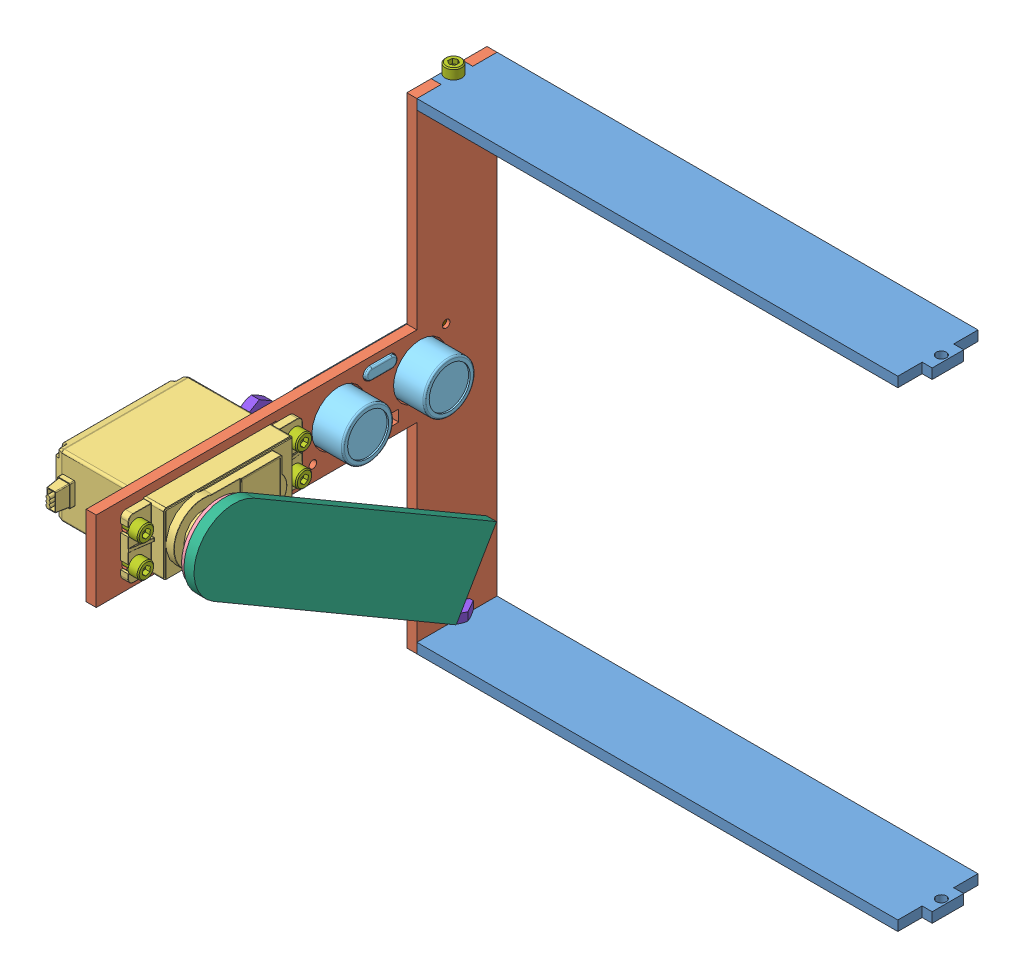
SolidWorks assembly midterm, configuration Default. Lengths in mm.
Overall size (184.49 158.75 127).
20 component instances, 9 part files, 38 mates.
Components (placement in the parent):
- midterm backwall-1: midterm backwall [Default] at (21.857 79.3906 28.0578) size (158.76 3.18 25.4)
- midterm backwall-2: midterm backwall [Default] at (21.857 -69.8294 28.0578) size (158.76 3.18 25.4)
- midtermfrontwall2-1: midtermfrontwall2 [Default] at (-54.343 6.3706 28.0578) x (0 0 -1) z (0 1 0) size (127 3.18 152.4)
- Standard Servo FS5106B-1: Standard Servo FS5106B [Default] at (-56.248 6.5281 107.0078) x (0 0 -1) z (1 0 0) size (55.2 19.69 44.46)
- Micro Servo Horn Round-1: Micro Servo Horn Round [Default] at (-40.2989 6.5281 117.5153) x (0 0.094238 0.99555) z (0 0.99555 -0.094238) size (23.65 4.35 23.65)
- HC-SR04 WITH CONFIGURATIONS-1: HC-SR04 WITH CONFIGURATIONS [With Oscillator] at (-59.223 7.3667 52.5952) x (0 0 -1) z (1 0 0) size (45.2 26.75 18.52)
- midterm arm-1: midterm arm [Default] at (-35.506 -15.8788 79.1261) x (0 0.863649 -0.504093) z (0 0.504093 0.863649) size (25.4 3.18 101.6)
- socket head cap screw_ai-1: socket head cap screw_ai [HX-SHCS 0.125-44x0.4375x0.4375-N] at (-55.433 -73.0044 28.0578) x (0 1 0) z (0 0 1) size (14.29 5.21 5.21)
- socket head cap screw_ai-2: socket head cap screw_ai [HX-SHCS 0.125-44x0.4375x0.4375-N] at (-55.433 85.7456 28.0578) x (0 -1 0) z (-0.546944 0 0.837169) size (14.29 5.21 5.21)
- socket head cap screw_ai-3: socket head cap screw_ai [HX-SHCS 0.125-44x0.4375x0.4375-N] at (-48.755 1.4481 81.9588) x (-1 0 0) z (0 0.924225 0.381849) size (14.29 5.21 5.21)
- socket head cap screw_ai-4: socket head cap screw_ai [HX-SHCS 0.125-44x0.4375x0.4375-N] at (-48.755 11.6081 81.9588) x (-1 0 0) z (0 -0.924225 -0.381849) size (14.29 5.21 5.21)
- socket head cap screw_ai-5: socket head cap screw_ai [HX-SHCS 0.125-44x0.4375x0.4375-N] at (-48.755 1.4481 132.0568) x (-1 0 0) z (0 0.924225 0.381849) size (14.29 5.21 5.21)
- socket head cap screw_ai-6: socket head cap screw_ai [HX-SHCS 0.125-44x0.4375x0.4375-N] at (-48.755 11.6081 132.0568) x (-1 0 0) z (0 -0.924225 -0.381849) size (14.29 5.21 5.21)
- machine screw nut hex_ai-1: machine screw nut hex_ai [MSHXNUT 0.125-44-S-N] at (-58.3201 1.4481 132.0568) x (0 0 -1) z (1 0 0) size (7.92 9.15 2.9)
- machine screw nut hex_ai-3: machine screw nut hex_ai [MSHXNUT 0.125-44-S-N] at (-57.024 11.6081 132.0568) x (0 0 -1) z (1 0 0) size (7.92 9.15 2.9)
- machine screw nut hex_ai-4: machine screw nut hex_ai [MSHXNUT 0.125-44-S-N] at (-58.084 1.4481 81.9588) x (0 0 -1) z (1 0 0) size (7.92 9.15 2.9)
- machine screw nut hex_ai-5: machine screw nut hex_ai [MSHXNUT 0.125-44-S-N] at (-65.9381 11.6081 81.9588) x (0 0 1) z (-1 0 0) size (7.92 9.15 2.9)
- machine screw nut hex_ai-8: machine screw nut hex_ai [MSHXNUT 0.125-44-S-N] at (-55.433 78.3479 28.0578) x (0.999955 0 -0.009478) z (0 1 0) size (7.92 9.15 2.9)
- machine screw nut hex_ai-9: machine screw nut hex_ai [MSHXNUT 0.125-44-S-N] at (-55.433 -65.7993 28.0578) x (-0.009669 0 0.999953) z (0 -1 0) size (7.92 9.15 2.9)
- socket button head cap screw_ai-7: socket button head cap screw_ai [SBHCSCREW 0.086-64x0.3125-HX-N] at (-64.2211 16.1167 31.4952) size (9.11 4.17 4.17)
Mates (geometry in assembly coordinates):
- Coincident19: coincident anti-aligned: plane of midterm backwall-2 through (21.857 -66.6494 28.0578) normal (0 1 0); plane of midtermfrontwall2-1 through (-54.343 -66.6494 28.0578) normal (0 -1 0)
- Coincident20: coincident anti-aligned: plane of midterm backwall-2 through (-57.523 -66.6494 23.0578) normal (0 0 -1); plane of midtermfrontwall2-1 through (-54.343 6.3706 23.0578) normal (0 0 1)
- Coincident21: coincident anti-aligned: plane of midterm backwall-1 through (-54.343 82.5706 15.3578) normal (-1 0 0); plane of midtermfrontwall2-1 through (-54.343 6.3706 28.0578) normal (1 0 0)
- Coincident22: coincident anti-aligned: plane of midtermfrontwall2-1 through (-54.343 6.3706 28.0578) normal (1 0 0); plane of Standard Servo FS5106B-1 through (-54.343 15.9896 79.4188) normal (-1 0 0)
- Parallel1: parallel aligned: plane of midtermfrontwall2-1 through (-57.523 19.0706 40.7578) normal (0 1 0); plane of Standard Servo FS5106B-1 through (-47.993 16.3706 126.5958) normal (0 1 0)
- Parallel2: parallel aligned: plane of midtermfrontwall2-1 through (-57.523 -6.3294 40.7578) normal (0 -1 0); plane of Standard Servo FS5106B-1 through (-47.993 -3.3144 126.5958) normal (0 -1 0)
- Coincident25: coincident anti-aligned: plane of midtermfrontwall2-1 through (-64.343 16.3706 127.3578) normal (0 -1 0); plane of Standard Servo FS5106B-1 through (-47.993 16.3706 126.5958) normal (0 1 0)
- Coincident26: coincident anti-aligned: plane of midtermfrontwall2-1 through (-64.343 16.3706 127.3578) normal (0 0 -1); plane of Standard Servo FS5106B-1 through (-47.993 -2.5524 127.3578) normal (0 0 1)
- Concentric1: concentric anti-aligned: cylinder of Standard Servo FS5106B-1 through (-38.786 6.5281 117.5153) axis (-1 0 0) radius 2.9; cone of Micro Servo Horn Round-1 through (-42.786 6.5281 117.5153) axis (1 0 0)
- Coincident35: coincident anti-aligned: plane of midtermfrontwall2-1 through (-57.523 6.3706 28.0578) normal (-1 0 0); plane of HC-SR04 WITH CONFIGURATIONS-1 through (-57.523 7.3667 52.5952) normal (1 0 0)
- Coincident36: coincident anti-aligned: plane of Standard Servo FS5106B-1 through (-42.786 6.5281 117.5153) normal (1 0 0); plane of Micro Servo Horn Round-1 through (-42.786 6.5281 117.5153) normal (-1 0 0)
- Coincident37: coincident anti-aligned: plane of Micro Servo Horn Round-1 through (-38.686 6.5281 117.5153) normal (1 0 0); plane of midterm arm-1 through (-38.686 6.5281 117.5153) normal (-1 0 0)
- Concentric2: concentric anti-aligned: circle of Micro Servo Horn Round-1; circle of midterm arm-1
- Concentric3: concentric anti-aligned: cylinder of midtermfrontwall2-1 through (-64.343 7.3667 65.5252) axis (1 0 0) radius 8.5; cylinder of HC-SR04 WITH CONFIGURATIONS-1 through (-45.523 7.3667 65.5252) axis (-1 0 0) radius 8
- Coincident39: coincident aligned: plane of midterm backwall-2 through (21.857 -69.8294 28.0578) normal (0 -1 0); plane of midtermfrontwall2-1 through (-57.523 -69.8294 15.3578) normal (0 -1 0)
- Coincident40: coincident aligned: plane of midterm backwall-2 through (-57.523 -69.8294 28.0578) normal (-1 0 0); plane of midtermfrontwall2-1 through (-57.523 6.3706 28.0578) normal (-1 0 0)
- Concentric5: concentric anti-aligned: cylinder of midterm backwall-2 through (-55.433 -69.8294 28.0578) axis (0 1 0) radius 1.59; cylinder of socket head cap screw_ai-1 through (-55.433 -104.7544 28.0578) axis (0 -1 0) radius 2.6035
- Coincident41: coincident anti-aligned: plane of midterm backwall-2 through (21.857 -69.8294 28.0578) normal (0 -1 0); plane of socket head cap screw_ai-1 through (-58.0365 -69.8294 28.0578) normal (0 1 0)
- Concentric6: concentric aligned: cylinder of Standard Servo FS5106B-1 through (-56.248 1.4481 81.9588) axis (1 0 0) radius 2.2225; cylinder of socket head cap screw_ai-3 through (-17.005 1.4481 81.9588) axis (1 0 0) radius 2.6035
- Coincident42: coincident anti-aligned: plane of Standard Servo FS5106B-1 through (-51.93 15.9896 79.4188) normal (1 0 0); plane of socket head cap screw_ai-3 through (-51.93 0.454 84.365) normal (-1 0 0)
- Concentric7: concentric aligned: cylinder of midtermfrontwall2-1 through (-64.343 11.6081 81.9588) axis (1 0 0) radius 2.2225; cylinder of socket head cap screw_ai-4 through (-17.005 11.6081 81.9588) axis (1 0 0) radius 2.6035
- Concentric8: concentric aligned: cylinder of Standard Servo FS5106B-1 through (-56.248 1.4481 132.0568) axis (1 0 0) radius 2.2225; cylinder of socket head cap screw_ai-5 through (-17.005 1.4481 132.0568) axis (1 0 0) radius 2.6035
- Coincident43: coincident anti-aligned: plane of Standard Servo FS5106B-1 through (-51.93 15.9896 134.5968) normal (1 0 0); plane of socket head cap screw_ai-5 through (-51.93 0.454 134.463) normal (-1 0 0)
- Concentric9: concentric aligned: cylinder of midtermfrontwall2-1 through (-64.343 11.6081 132.0568) axis (1 0 0) radius 2.2225; cylinder of socket head cap screw_ai-6 through (-17.005 11.6081 132.0568) axis (1 0 0) radius 2.6035
- Coincident44: coincident anti-aligned: plane of Standard Servo FS5106B-1 through (-51.93 15.9896 79.4188) normal (1 0 0); plane of socket head cap screw_ai-4 through (-51.93 12.6022 79.5526) normal (-1 0 0)
- Coincident45: coincident anti-aligned: plane of Standard Servo FS5106B-1 through (-51.93 15.9896 134.5968) normal (1 0 0); plane of socket head cap screw_ai-6 through (-51.93 12.6022 129.6506) normal (-1 0 0)
- Coincident46: coincident anti-aligned: plane of midterm backwall-1 through (21.857 82.5706 28.0578) normal (0 1 0); plane of socket head cap screw_ai-2 through (-53.2534 82.5706 29.4817) normal (0 -1 0)
- Concentric10: concentric aligned: circle of midterm backwall-1; cylinder of socket head cap screw_ai-2 through (-55.433 117.4956 28.0578) axis (0 1 0) radius 2.6035
- Concentric12: concentric aligned: cylinder of socket head cap screw_ai-5 through (-17.005 1.4481 132.0568) axis (1 0 0) radius 1.5875; cylinder of machine screw nut hex_ai-1 through (-83.3576 1.4481 132.0568) axis (1 0 0) radius 1.5875
- Concentric13: concentric aligned: cylinder of socket head cap screw_ai-6 through (-17.005 11.6081 132.0568) axis (1 0 0) radius 1.5875; cylinder of machine screw nut hex_ai-3 through (-82.0615 11.6081 132.0568) axis (1 0 0) radius 1.5875
- Concentric14: concentric aligned: cylinder of socket head cap screw_ai-3 through (-17.005 1.4481 81.9588) axis (1 0 0) radius 1.5875; cylinder of machine screw nut hex_ai-4 through (-83.1215 1.4481 81.9588) axis (1 0 0) radius 1.5875
- Concentric15: concentric aligned: cone of socket head cap screw_ai-4 through (-63.0425 11.6081 81.9588) axis (-1 0 0); cylinder of machine screw nut hex_ai-5 through (-40.9006 11.6081 81.9588) axis (-1 0 0) radius 1.5875
- Coincident47: coincident anti-aligned: plane of socket head cap screw_ai-4 through (-63.0425 12.0829 80.8097) normal (-1 0 0); plane of machine screw nut hex_ai-5 through (-63.0425 11.6081 74.034) normal (1 0 0)
- Concentric16: concentric aligned: cylinder of socket head cap screw_ai-2 through (-55.433 117.4956 28.0578) axis (0 1 0) radius 1.5875; cylinder of machine screw nut hex_ai-8 through (-55.433 53.3104 28.0578) axis (0 1 0) radius 1.5875
- Concentric17: concentric anti-aligned: cylinder of socket head cap screw_ai-1 through (-55.433 -104.7544 28.0578) axis (0 -1 0) radius 1.5875; circle of machine screw nut hex_ai-9
- Coincident48: coincident anti-aligned: plane of midterm backwall-1 through (-57.523 82.5706 33.0578) normal (0 0 1); plane of midtermfrontwall2-1 through (-54.343 82.5706 33.0578) normal (0 0 -1)
- Coincident49: coincident anti-aligned: plane of midterm backwall-1 through (21.857 79.3906 28.0578) normal (0 -1 0); plane of midtermfrontwall2-1 through (-54.343 79.3906 26.4678) normal (0 1 0)
- Concentric20: concentric aligned: cylinder of midtermfrontwall2-1 through (-47.523 16.1167 31.4952) axis (-1 0 0) radius 1.2; cylinder of socket button head cap screw_ai-7 through (-64.2211 16.1167 31.4952) axis (-1 0 0) radius 2.0828
